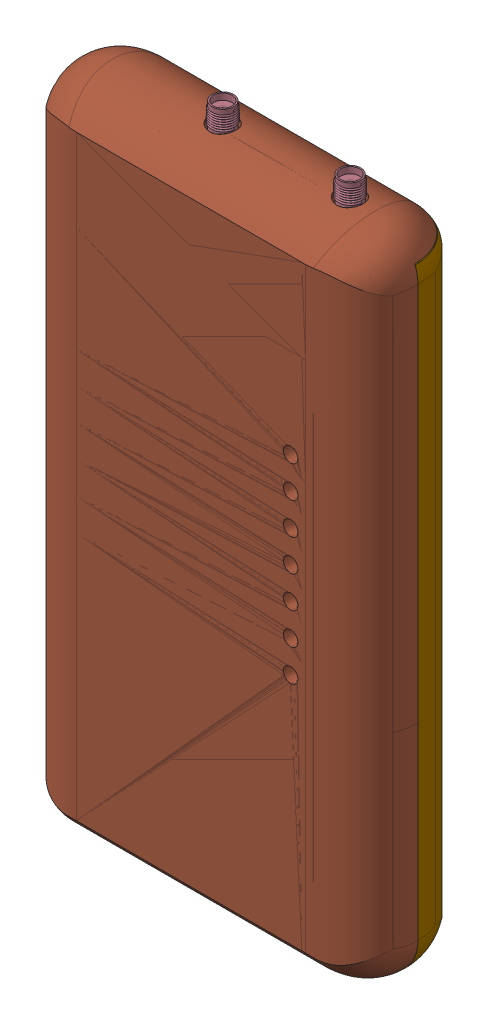
SolidWorks assembly TARPON_PCB, configuration Default. Lengths in mm.
Overall size (82 158.5 25).
29 component instances, 13 part files, 17 mates.
Components (placement in the parent):
- TARPON_PCB.step-1: TARPON_PCB.step [Default] at origin size (65 90 18.2)
  - PinHeader_1x04_P2.54mm_Vertical.step-1: PinHeader_1x04_P2.54mm_Vertical.step [Default] at (60.588 -78.74 1.65) x (-1 0 0) z (0 0 1) size (2.54 10.16 11.54)
    - SOLID.step-1: SOLID.step [Default] at origin size (2.54 10.16 11.54)
  - Product_TF Micro SD Card Memory Modul Arduino.step-1: Product_TF Micro SD Card Memory Modul Arduino.step [Default] at (45.4 -88.21 4.15) size (24 41.8 11.46)
    - COMPOUND.step-1: COMPOUND.step [Default] at origin size (24 41.8 11.46)
  - ss12f44g4.step-1: ss12f44g4.step [Default] at (26.3025 -85.4 1.65) x (0 1 0) z (0 0 1) size (3.6 7.98 8.17)
    - COMPOUND-0.step-1: COMPOUND-0.step [Default] at origin size (3.6 7.98 8.17)
  - PinHeader_1x04_P2.54mm_Vertical.step-2: PinHeader_1x04_P2.54mm_Vertical.step [Default] at (60.6091 -54.3 1.65) x (-1 0 0) z (0 0 1) size (2.54 10.16 11.54)
    - SOLID.step-1: SOLID.step [Default] at origin size (2.54 10.16 11.54)
  - esp32_dev_kit_v1_asm.step-1: esp32_dev_kit_v1_asm.step [Default] at (15.494 -28.852 4.15) x (-1 0 0) z (0 0 1) size (28.15 51.51 15.02)
    - COMPOUND-1.step-1: COMPOUND-1.step [Default] at origin size (28.15 51.51 15.02)
  - PinHeader_1x04_P2.54mm_Vertical.step-3: PinHeader_1x04_P2.54mm_Vertical.step [Default] at (2.7091 -24.605 1.65) x (-1 0 0) z (0 0 1) size (2.54 10.16 11.54)
    - SOLID.step-1: SOLID.step [Default] at origin size (2.54 10.16 11.54)
  - K7803-500R3.step-1: K7803-500R3.step [Default] at (42.306 -36.8 1.65) x (0 -1 0) z (-1 0 0) size (11.6 14.26 7.55)
    - COMPOUND-2.step-1: COMPOUND-2.step [Default] at origin size (11.6 14.26 7.55)
  - RFM95W v5 pins.step-1: RFM95W v5 pins.step [Default] at (30.7718 -30.4959 4.15) x (1 0 0) z (0 -1 0) size (25.4 12.17 29.21)
    - COMPOUND-3.step-1: COMPOUND-3.step [Default] at origin size (25.4 12.17 29.21)
  - Screw-Terminal-P5.08.step-1: Screw-Terminal-P5.08.step [Default] at (8.86 -89.1 1.65) size (10.89 7.8 14)
    - COMPOUND-4.step-1: COMPOUND-4.step [Default] at origin size (10.89 7.8 14)
  - PinHeader_1x04_P2.54mm_Vertical.step-4: PinHeader_1x04_P2.54mm_Vertical.step [Default] at (60.5971 -68.6 1.65) x (-1 0 0) z (0 0 1) size (2.54 10.16 11.54)
    - SOLID.step-1: SOLID.step [Default] at origin size (2.54 10.16 11.54)
  - _autosave-TARPON_PCB PCB.step-1: _autosave-TARPON_PCB PCB.step [Default] at origin size (65 90 1.6)
- Part1boxV2-1: Part1boxV2 [Default] at (-28.0363 -109.9151 -9.4) x (1 0 0) z (0 -1 0) size (82.67 16.81 154)
- 18650 Li Ion Battery-1: 18650 Li Ion Battery [Default] at (0.38 -101 3.1) x (0 -0.276486 -0.961018) z (1 0 0) size (18 18 65.81)
- 18650 Li Ion Battery-2: 18650 Li Ion Battery [Default] at (0.38 -121.6 3.1) x (0 -0.140585 -0.990069) z (1 0 0) size (18 18 65.81)
- Part1lidV2-1: Part1lidV2 [Default] at (-30.0363 -109.9151 -9.4) x (1 0 0) z (0 -1 0) size (82.75 26.21 154)
- USB type-B female PCB-1: USB type-B female PCB [Default] at (12.3 3.4891 -2.95) x (0 0 1) z (-1 0 0) size (15.32 13.63 16.6)
- Molex - 73391-0060-1: Molex - 73391-0060 [Default] at (27.5 11.6 3.1) x (1 0 0) z (0 1 0) size (6.08 6.08 12.55)
- Molex - 73391-0060-2: Molex - 73391-0060 [Default] at (57.5 11.6 3.1) x (1 0 0) z (0 1 0) size (6.08 6.08 12.55)
Mates (geometry in assembly coordinates):
- Concentric1: concentric aligned: cylinder of TARPON_PCB.step-1/_autosave-TARPON_PCB PCB.step-1 through (4 -4 -0.8) axis (0 0 1) radius 1.6; circle of Part1-1
- Concentric2: concentric aligned: cylinder of TARPON_PCB.step-1/_autosave-TARPON_PCB PCB.step-1 through (61 -4 -0.8) axis (0 0 1) radius 1.6; circle of Part1-1
- Coincident1: coincident anti-aligned: plane of TARPON_PCB.step-1/_autosave-TARPON_PCB PCB.step-1 through (32.5006 -45.0008 0) normal (0 0 -1); circle of Part1-1
- Concentric3: concentric anti-aligned: cylinder of Part1boxV1-1 through (0 -101 3.1) axis (1 0 0) radius 9.8; cylinder of 18650 Li Ion Battery-1 through (65.78 -101 3.1) axis (-1 0 0) radius 9
- Coincident2: coincident anti-aligned: circle of Part1boxV1-1; plane of 18650 Li Ion Battery-1 through (0 -101 3.1) normal (-1 0 0)
- Concentric4: concentric anti-aligned: cylinder of Part1boxV1-1 through (0 -121.6 3.1) axis (1 0 0) radius 9.8; cylinder of 18650 Li Ion Battery-2 through (65.78 -121.6 3.1) axis (-1 0 0) radius 9
- Coincident3: coincident anti-aligned: circle of Part1boxV1-1; plane of 18650 Li Ion Battery-2 through (0 -121.6 3.1) normal (-1 0 0)
- Coincident4: coincident anti-aligned: plane of Part1boxV1-1 through (-27 9.6 3.1) normal (0 0 1); plane of Part1lidV2-1 through (73.5 -0.4 3.1) normal (0 0 -1)
- Concentric5: concentric anti-aligned: cylinder of Part1lidV2-1 through (57.5 19.6 3.1) axis (0 -1 0) radius 3.125; cylinder of Molex - 73391-0060-2 through (57.5 15.1 3.1) axis (0 1 0) radius 2.54
- Coincident12: coincident aligned: line of Part1boxV1-1 through (-8.5 0.2 3.1) axis (0 -1 0); line of Part1lidV2-1 through (-8.5 0.4 3.1) axis (0 -1 0)
- Concentric6: concentric anti-aligned: cylinder of Part1lidV2-1 through (27.5 19.6 3.1) axis (0 -1 0) radius 3.125; cylinder of Molex - 73391-0060-1 through (27.5 15.1 3.1) axis (0 1 0) radius 2.54
- Distance4: distance = 0.2 mm anti-aligned: plane of Part1boxV1-1 through (-9.8 0.2 5.6286) normal (0 1 0); plane of Part1lidV2-1 through (-8.5 0.4 3.1) normal (0 -1 0)
- Coincident14: coincident anti-aligned: plane of Part1lidV2-1 through (-30.0363 16.9 -9.4) normal (0 -1 0); plane of Molex - 73391-0060-1 through (24.46 16.9 6.14) normal (0 1 0)
- Coincident15: coincident anti-aligned: plane of Part1lidV2-1 through (-30.0363 16.9 -9.4) normal (0 -1 0); plane of Molex - 73391-0060-2 through (54.46 16.9 6.14) normal (0 1 0)
- Distance1: distance = 0.2 mm anti-aligned: plane of Part1lidV2-1 through (-8.5 14.4391 9.35) normal (0 -1 0); plane of USB type-B female PCB-1 through (-4.3 14.2391 -2.95) normal (0 1 0)
- Distance2: distance = 0.2 mm anti-aligned: plane of Part1lidV2-1 through (-8.5 3.3391 9.35) normal (0 0 -1); plane of USB type-B female PCB-1 through (-4.3 3.4891 9.15) normal (0 0 1)
- Distance3: distance = 4.8 mm anti-aligned: plane of Part1lidV2-1 through (0.5 4.6 3.1) normal (1 0 0); plane of USB type-B female PCB-1 through (-4.3 3.4891 -2.95) normal (-1 0 0)
